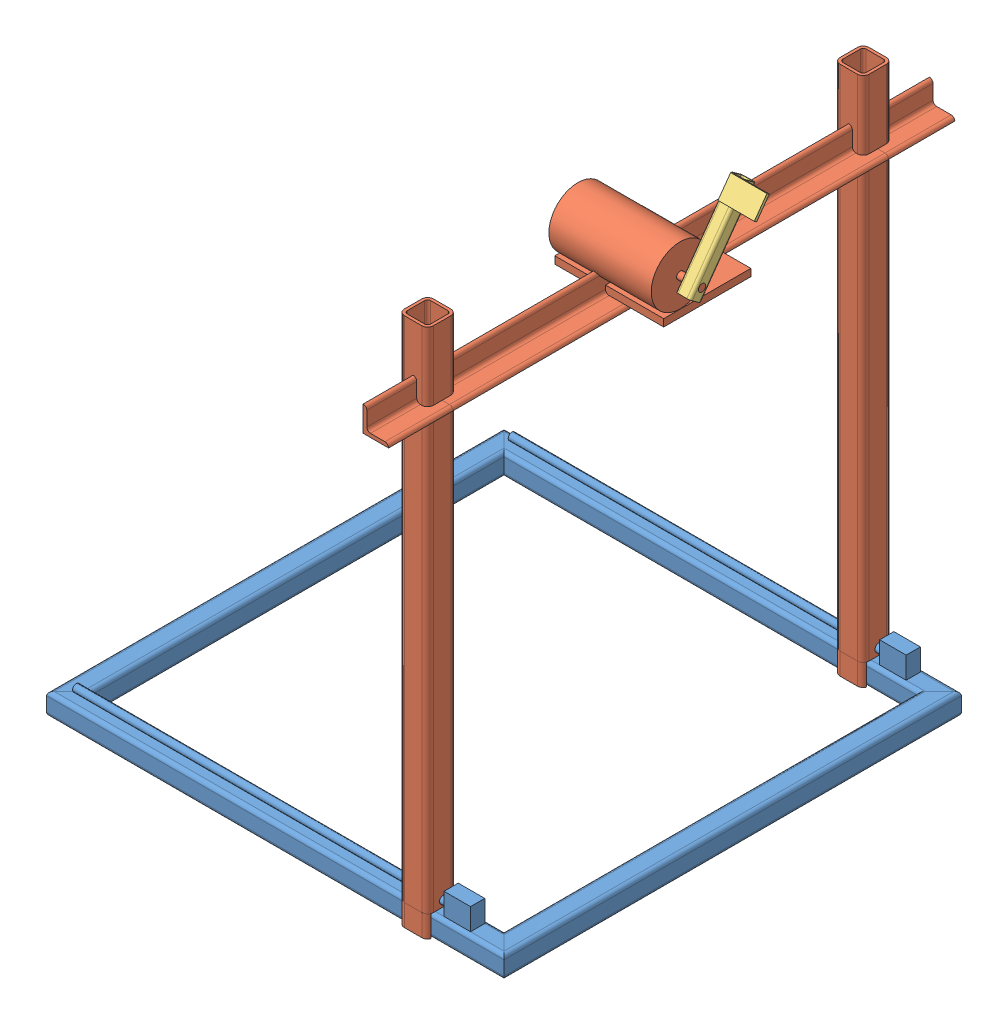
SolidWorks assembly automatic total, configuration Default. Lengths in mm.
Overall size (660.63 788.33 779.86).
3 component instances, 3 part files, 4 mates.
Components (placement in the parent):
- automatic base-1: automatic base [Default<As Machined>] at (322.9985 276.4792 472.7533) size (630 60 630)
- automatic motor-1: automatic motor [Default<As Machined>] at (519.4623 953.7168 721.1618) size (180 730 779.86)
- GRIPPER-1: GRIPPER [Default<As Machined>] at (624.6262 935.8605 520.3207) x (0 0.814002 -0.580863) z (1 0 0) size (130 24 54)
Mates (geometry in assembly coordinates):
- Concentric1: concentric aligned: cylinder of automatic base-1 through (34.1554 301.4725 773.1213) axis (1 0 0) radius 5; cylinder of automatic motor-1 through (434.4623 301.4725 773.1213) axis (1 0 0) radius 5
- Parallel1: parallel anti-aligned: plane of automatic base-1 through (622.9985 291.4792 162.9533) normal (0 1 0); plane of automatic motor-1 through (531.4623 262.6986 162.4234) normal (0 -1 0)
- Concentric5: concentric anti-aligned: cylinder of automatic motor-1 through (634.6262 948.0706 511.6077) axis (-1 0 0) radius 5; cylinder of GRIPPER-1 through (599.6262 948.0706 511.6077) axis (1 0 0) radius 5
- Coincident4: coincident aligned: plane of automatic motor-1 through (634.6262 948.0706 511.6077) normal (1 0 0); plane of GRIPPER-1 through (634.6262 1045.1659 449.6925) normal (1 0 0)
